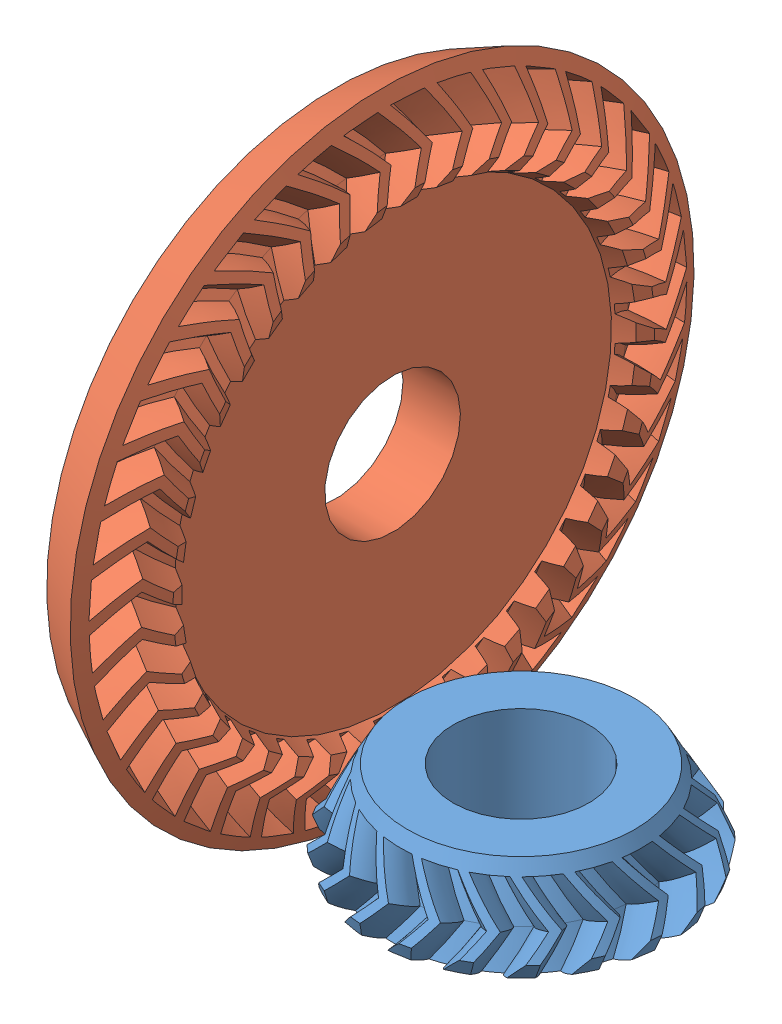
SolidWorks assembly Double Helical Bevel Test Assembly, configuration Default. Lengths in mm.
Overall size (129.34 130.67 100.6).
2 component instances, 2 part files, 2 mates.
Components (placement in the parent):
- Double Helical Inner Bevel Gear-1: Double Helical Inner Bevel Gear [Default] at origin size (77.34 38.67 30.94)
- Double Helical Outer Bevel Gear-1: Double Helical Outer Bevel Gear [Default] x (0 0.382964 -0.923763) z (0 -0.923763 -0.382964) size (60.69 118.21 116.29)
Mates (geometry in assembly coordinates):
- Coincident1: coincident aligned: line of Double Helical Inner Bevel Gear-1 through (63.5 0 0) axis (0 -1 0); line of Double Helical Outer Bevel Gear-1 through (0 0 0) axis (-1 0 0)
- Coincident2: coincident: point of Double Helical Inner Bevel Gear-1; point of Double Helical Outer Bevel Gear-1
